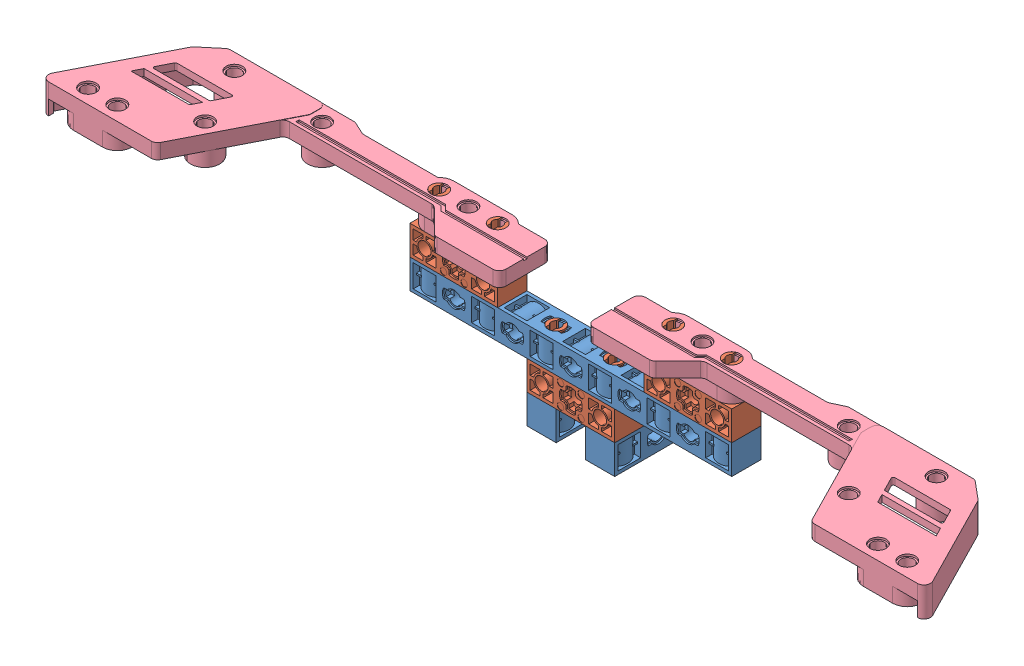
SolidWorks assembly Subconjunto Aileron, configuration Default. Lengths in mm.
Overall size (271.25 45.1 54).
10 component instances, 4 part files, 18 mates.
Components (placement in the parent):
- Viga alternada-1: Viga alternada [Viga alternada de 11 (Preta)] at (29.1408 56.8892 76.5637) size (99 9 9)
- Viga com pinos-2: Viga com pinos [Viga com pinos (Cinzenta)] at (65.1408 65.8892 76.5637) size (27 27 9)
- Viga com pinos-3: Viga com pinos [Viga com pinos (Branca)] at (29.1408 47.8892 76.5637) size (27 27 9)
- Viga alternada-2: Viga alternada [Viga alternada de 3 (Preta)] at (38.1408 38.8892 67.5637) x (0 0 -1) z (-1 0 0) size (27 9 9)
- Pino Perpendicular-1: Pino Perpendicular [Default] at (38.1408 43.3892 58.5637) x (-1 0 0) z (0 0 1) size (6 18 6)
- Asa-3: Asa [Asa Direita] at (65.1408 79.3892 76.5637) x (-1 0 0) z (0 0 1) size (122.12 9.1 36.5)
- Viga com pinos-6: Viga com pinos [Viga com pinos (Cinzenta)] at (-6.8592 65.8892 76.5637) x (-1 0 0) z (0 0 -1) size (27 27 9)
- Viga alternada-4: Viga alternada [Viga alternada de 3 (Preta)] at (20.1408 38.8892 67.5637) x (0 0 -1) z (-1 0 0) size (27 9 9)
- Asa-5: Asa [Asa Esquerda] at (38.1408 79.3892 76.5637) x (-1 0 0) z (0 0 1) size (122.12 9.1 36.5)
- Pino Perpendicular-3: Pino Perpendicular [Default] at (20.1408 43.3892 58.5637) x (1 0 0) z (0 0 -1) size (6 18 6)
Mates (geometry in assembly coordinates):
- Concentric1: concentric aligned: cylinder of Viga alternada-1 through (74.1408 52.3892 76.5637) axis (0 1 0) radius 2; cylinder of Viga com pinos-2 through (74.1408 52.3892 76.5637) axis (0 1 0) radius 2
- Concentric2: concentric aligned: cylinder of Viga alternada-1 through (56.1408 52.3892 76.5637) axis (0 1 0) radius 2; cylinder of Viga com pinos-2 through (56.1408 52.3892 76.5637) axis (0 1 0) radius 2
- Coincident1: coincident aligned: plane of Viga alternada-1 through (29.1408 52.3892 76.5637) normal (0 -1 0); plane of Viga com pinos-2 through (74.1408 52.3892 76.5637) normal (0 -1 0)
- Concentric3: concentric anti-aligned: cylinder of Viga alternada-1 through (38.1408 52.3892 76.5637) axis (0 1 0) radius 2; cylinder of Viga com pinos-3 through (38.1408 61.3892 76.5637) axis (0 -1 0) radius 2
- Concentric4: concentric anti-aligned: cylinder of Viga alternada-1 through (20.1408 52.3892 76.5637) axis (0 1 0) radius 2; cylinder of Viga com pinos-3 through (20.1408 61.3892 76.5637) axis (0 -1 0) radius 2
- Coincident2: coincident aligned: plane of Viga alternada-1 through (29.1408 61.3892 76.5637) normal (0 1 0); plane of Viga com pinos-3 through (20.1408 61.3892 76.5637) normal (0 1 0)
- Concentric5: concentric aligned: cylinder of Viga alternada-2 through (38.1408 43.3892 58.5637) axis (0 -1 0) radius 2; cylinder of Pino Perpendicular-1 through (38.1408 34.3892 58.5637) axis (0 -1 0) radius 2
- Coincident3: coincident anti-aligned: plane of Viga alternada-2 through (37.1408 36.3892 49.5637) normal (1 0 0); plane of Pino Perpendicular-1 through (37.1408 43.3892 58.5637) normal (-1 0 0)
- Coincident4: coincident aligned: plane of Viga alternada-2 through (38.1408 34.3892 67.5637) normal (0 -1 0); plane of Pino Perpendicular-1 through (38.1408 34.3892 58.5637) normal (0 -1 0)
- Concentric6: concentric anti-aligned: cylinder of Viga com pinos-3 through (38.1408 34.3892 76.5637) axis (0 1 0) radius 2; cylinder of Viga alternada-2 through (38.1408 43.3892 76.5637) axis (0 -1 0) radius 2
- Coincident5: coincident aligned: plane of Viga com pinos-3 through (42.6408 52.3892 81.0637) normal (1 0 0); plane of Viga alternada-2 through (42.6408 34.3892 81.0637) normal (1 0 0)
- Coincident6: coincident aligned: plane of Viga com pinos-3 through (38.1408 34.3892 76.5637) normal (0 -1 0); plane of Viga alternada-2 through (38.1408 34.3892 67.5637) normal (0 -1 0)
- Concentric8: concentric anti-aligned: cylinder of Viga com pinos-2 through (56.1408 79.3892 76.5637) axis (0 -1 0) radius 2; cylinder of Asa-3 through (56.1408 70.3892 76.5637) axis (0 1 0) radius 2
- Concentric9: concentric anti-aligned: cylinder of Viga com pinos-2 through (74.1408 79.3892 76.5637) axis (0 -1 0) radius 2; cylinder of Asa-3 through (74.1408 70.3892 76.5637) axis (0 1 0) radius 2
- Coincident7: coincident aligned: plane of Viga com pinos-2 through (56.1408 79.3892 76.5637) normal (0 1 0); plane of Asa-3 through (74.1408 79.3892 76.5637) normal (0 1 0)
- Concentric11: concentric anti-aligned: cylinder of Viga com pinos-6 through (2.1408 79.3892 76.5637) axis (0 -1 0) radius 2; cylinder of Asa-5 through (2.1408 77.3892 76.5637) axis (0 1 0) radius 2
- Concentric12: concentric anti-aligned: cylinder of Viga com pinos-6 through (-15.8592 79.3892 76.5637) axis (0 -1 0) radius 1.5; cylinder of Asa-5 through (-15.8592 77.3892 76.5637) axis (0 1 0) radius 2
- Coincident8: coincident aligned: plane of Viga com pinos-6 through (2.1408 79.3892 76.5637) normal (0 1 0); plane of Asa-5 through (47.1408 79.3892 76.5637) normal (0 1 0)
